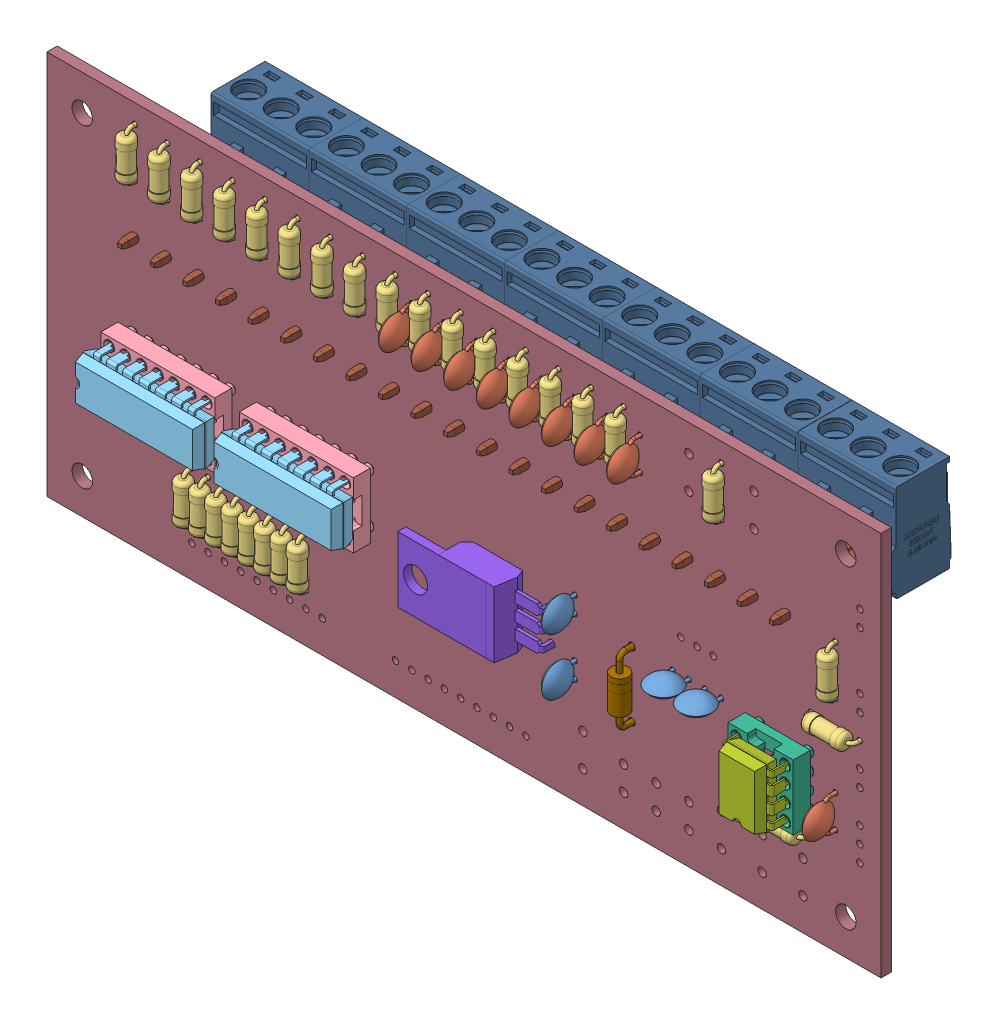
SolidWorks assembly minilab, configuration Predeterminado. Lengths in mm.
Overall size (130 60 30.78).
129 component instances, 13 part files, 0 mates.
Components (placement in the parent):
- C_Disc_D5.0mm_W2.5mm_P2.50mm-1: C_Disc_D5.0mm_W2.5mm_P2.50mm [Predeterminado] at (175.26 -113.03 1.65) x (0 -1 0) z (0 0 1) size (5 2.5 7.1)
  - SOLID_1-1: SOLID_1 [Predeterminado] at origin size (5 2.5 7.1)
- C_Disc_D5.0mm_W2.5mm_P5.00mm-1: C_Disc_D5.0mm_W2.5mm_P5.00mm [Predeterminado] at (170.18 -82.55 1.65) x (0 1 0) z (0 0 1) size (5.5 2.5 7.1)
  - SOLID_1_2-1: SOLID_1_2 [Predeterminado] at origin size (5.5 2.5 7.1)
- R_Axial_DIN0207_L6.3mm_D2.5mm_P7.62mm_Horizontal-1: R_Axial_DIN0207_L6.3mm_D2.5mm_P7.62mm_Horizontal [Predeterminado] at (121.92 -82.55 1.65) x (0 1 0) z (0 0 1) size (8.22 2.5 5.5)
  - SOLID_1_3-1: SOLID_1_3 [Predeterminado] at origin size (8.22 2.5 5.5)
- C_Disc_D5.0mm_W2.5mm_P2.50mm-2: C_Disc_D5.0mm_W2.5mm_P2.50mm [Predeterminado] at (190.52 -106.68 1.65) size (5 2.5 7.1)
  - SOLID_1-1: SOLID_1 [Predeterminado] at origin size (5 2.5 7.1)
- R_Axial_DIN0207_L6.3mm_D2.5mm_P7.62mm_Horizontal-2: R_Axial_DIN0207_L6.3mm_D2.5mm_P7.62mm_Horizontal [Predeterminado] at (182.88 -74.93 1.65) x (0 -1 0) z (0 0 1) size (8.22 2.5 5.5)
  - SOLID_1_3-1: SOLID_1_3 [Predeterminado] at origin size (8.22 2.5 5.5)
- R_Axial_DIN0207_L6.3mm_D2.5mm_P7.62mm_Horizontal-3: R_Axial_DIN0207_L6.3mm_D2.5mm_P7.62mm_Horizontal [Predeterminado] at (198.12 -82.55 1.65) x (0 1 0) z (0 0 1) size (8.22 2.5 5.5)
  - SOLID_1_3-1: SOLID_1_3 [Predeterminado] at origin size (8.22 2.5 5.5)
- C_Disc_D5.0mm_W2.5mm_P5.00mm-2: C_Disc_D5.0mm_W2.5mm_P5.00mm [Predeterminado] at (175.26 -82.51 1.65) x (0 1 0) z (0 0 1) size (5.5 2.5 7.1)
  - SOLID_1_2-1: SOLID_1_2 [Predeterminado] at origin size (5.5 2.5 7.1)
- DIP-14_W7.62mm_Socket-1: DIP-14_W7.62mm_Socket [Predeterminado] at (106.675 -110.48 1.65) x (0 1 0) z (0 0 1) size (10.16 17.78 7.79)
  - SOLID_1_4-1: SOLID_1_4 [Predeterminado] at origin size (10.16 17.78 7.79)
- DIP-14_W7.62mm_1-1: DIP-14_W7.62mm_1 [Predeterminado] at (106.675 -110.48 5.65) x (0 1 0) z (0 0 1) size (7.87 19.05 6.98)
  - SOLID_1_5-1: SOLID_1_5 [Predeterminado] at origin size (7.87 19.05 6.98)
- DIP-8_W7.62mm_Socket-1: DIP-8_W7.62mm_Socket [Predeterminado] at (212.06 -114.3 1.65) x (-1 0 0) z (0 0 1) size (10.16 10.16 7.79)
  - SOLID_1_6-1: SOLID_1_6 [Predeterminado] at origin size (10.16 10.16 7.79)
- DIP-8_W7.62mm_1-1: DIP-8_W7.62mm_1 [Predeterminado] at (212.06 -114.3 5.65) x (-1 0 0) z (0 0 1) size (7.87 9.27 6.98)
  - SOLID_1_7-1: SOLID_1_7 [Predeterminado] at origin size (7.87 9.27 6.98)
- R_Axial_DIN0207_L6.3mm_D2.5mm_P7.62mm_Horizontal-4: R_Axial_DIN0207_L6.3mm_D2.5mm_P7.62mm_Horizontal [Predeterminado] at (127 -82.55 1.65) x (0 1 0) z (0 0 1) size (8.22 2.5 5.5)
  - SOLID_1_3-1: SOLID_1_3 [Predeterminado] at origin size (8.22 2.5 5.5)
- R_Axial_DIN0207_L6.3mm_D2.5mm_P7.62mm_Horizontal-5: R_Axial_DIN0207_L6.3mm_D2.5mm_P7.62mm_Horizontal [Predeterminado] at (125.73 -116.84 1.65) x (0 -1 0) z (0 0 1) size (8.22 2.5 5.5)
  - SOLID_1_3-1: SOLID_1_3 [Predeterminado] at origin size (8.22 2.5 5.5)
- C_Disc_D5.0mm_W2.5mm_P5.00mm-3: C_Disc_D5.0mm_W2.5mm_P5.00mm [Predeterminado] at (149.86 -82.55 1.65) x (0 1 0) z (0 0 1) size (5.5 2.5 7.1)
  - SOLID_1_2-1: SOLID_1_2 [Predeterminado] at origin size (5.5 2.5 7.1)
- TO-220-3_Horizontal_TabUp-1: TO-220-3_Horizontal_TabUp [Predeterminado] at (171.66 -107.46 1.65) x (0 -1 0) z (0 0 1) size (10.25 19.74 12.58)
  - SOLID_1_8-1: SOLID_1_8 [Predeterminado] at origin size (10.25 19.74 12.58)
- R_Axial_DIN0207_L6.3mm_D2.5mm_P7.62mm_Horizontal-6: R_Axial_DIN0207_L6.3mm_D2.5mm_P7.62mm_Horizontal [Predeterminado] at (133.35 -116.84 1.65) x (0 -1 0) z (0 0 1) size (8.22 2.5 5.5)
  - SOLID_1_3-1: SOLID_1_3 [Predeterminado] at origin size (8.22 2.5 5.5)
- R_Axial_DIN0207_L6.3mm_D2.5mm_P7.62mm_Horizontal-7: R_Axial_DIN0207_L6.3mm_D2.5mm_P7.62mm_Horizontal [Predeterminado] at (120.65 -116.84 1.65) x (0 -1 0) z (0 0 1) size (8.22 2.5 5.5)
  - SOLID_1_3-1: SOLID_1_3 [Predeterminado] at origin size (8.22 2.5 5.5)
- C_Disc_D5.0mm_W2.5mm_P5.00mm-4: C_Disc_D5.0mm_W2.5mm_P5.00mm [Predeterminado] at (180.34 -82.51 1.65) x (0 1 0) z (0 0 1) size (5.5 2.5 7.1)
  - SOLID_1_2-1: SOLID_1_2 [Predeterminado] at origin size (5.5 2.5 7.1)
- R_Axial_DIN0207_L6.3mm_D2.5mm_P7.62mm_Horizontal-8: R_Axial_DIN0207_L6.3mm_D2.5mm_P7.62mm_Horizontal [Predeterminado] at (115.57 -116.84 1.65) x (0 -1 0) z (0 0 1) size (8.22 2.5 5.5)
  - SOLID_1_3-1: SOLID_1_3 [Predeterminado] at origin size (8.22 2.5 5.5)
- R_Axial_DIN0207_L6.3mm_D2.5mm_P7.62mm_Horizontal-9: R_Axial_DIN0207_L6.3mm_D2.5mm_P7.62mm_Horizontal [Predeterminado] at (157.48 -74.93 1.65) x (0 -1 0) z (0 0 1) size (8.22 2.5 5.5)
  - SOLID_1_3-1: SOLID_1_3 [Predeterminado] at origin size (8.22 2.5 5.5)
- R_Axial_DIN0207_L6.3mm_D2.5mm_P7.62mm_Horizontal-10: R_Axial_DIN0207_L6.3mm_D2.5mm_P7.62mm_Horizontal [Predeterminado] at (142.24 -82.55 1.65) x (0 1 0) z (0 0 1) size (8.22 2.5 5.5)
  - SOLID_1_3-1: SOLID_1_3 [Predeterminado] at origin size (8.22 2.5 5.5)
- C_Disc_D5.0mm_W2.5mm_P5.00mm-5: C_Disc_D5.0mm_W2.5mm_P5.00mm [Predeterminado] at (215.88 -110.54 1.65) x (0 -1 0) z (0 0 1) size (5.5 2.5 7.1)
  - SOLID_1_2-1: SOLID_1_2 [Predeterminado] at origin size (5.5 2.5 7.1)
- R_Axial_DIN0207_L6.3mm_D2.5mm_P7.62mm_Horizontal-11: R_Axial_DIN0207_L6.3mm_D2.5mm_P7.62mm_Horizontal [Predeterminado] at (123.19 -116.84 1.65) x (0 -1 0) z (0 0 1) size (8.22 2.5 5.5)
  - SOLID_1_3-1: SOLID_1_3 [Predeterminado] at origin size (8.22 2.5 5.5)
- D_DO-41_SOD81_P10.16mm_Horizontal-1: D_DO-41_SOD81_P10.16mm_Horizontal [Predeterminado] at (184.15 -106.68 1.65) x (0 -1 0) z (0 0 1) size (10.96 2.72 5.71)
  - SOLID_1_9-1: SOLID_1_9 [Predeterminado] at origin size (10.96 2.72 5.71)
- R_Axial_DIN0207_L6.3mm_D2.5mm_P7.62mm_Horizontal-12: R_Axial_DIN0207_L6.3mm_D2.5mm_P7.62mm_Horizontal [Predeterminado] at (116.84 -82.55 1.65) x (0 1 0) z (0 0 1) size (8.22 2.5 5.5)
  - SOLID_1_3-1: SOLID_1_3 [Predeterminado] at origin size (8.22 2.5 5.5)
- R_Axial_DIN0207_L6.3mm_D2.5mm_P7.62mm_Horizontal-13: R_Axial_DIN0207_L6.3mm_D2.5mm_P7.62mm_Horizontal [Predeterminado] at (132.08 -82.55 1.65) x (0 1 0) z (0 0 1) size (8.22 2.5 5.5)
  - SOLID_1_3-1: SOLID_1_3 [Predeterminado] at origin size (8.22 2.5 5.5)
- R_Axial_DIN0207_L6.3mm_D2.5mm_P7.62mm_Horizontal-14: R_Axial_DIN0207_L6.3mm_D2.5mm_P7.62mm_Horizontal [Predeterminado] at (172.72 -74.93 1.65) x (0 -1 0) z (0 0 1) size (8.22 2.5 5.5)
  - SOLID_1_3-1: SOLID_1_3 [Predeterminado] at origin size (8.22 2.5 5.5)
- R_Axial_DIN0207_L6.3mm_D2.5mm_P7.62mm_Horizontal-15: R_Axial_DIN0207_L6.3mm_D2.5mm_P7.62mm_Horizontal [Predeterminado] at (177.8 -74.93 1.65) x (0 -1 0) z (0 0 1) size (8.22 2.5 5.5)
  - SOLID_1_3-1: SOLID_1_3 [Predeterminado] at origin size (8.22 2.5 5.5)
- R_Axial_DIN0207_L6.3mm_D2.5mm_P7.62mm_Horizontal-16: R_Axial_DIN0207_L6.3mm_D2.5mm_P7.62mm_Horizontal [Predeterminado] at (111.76 -82.55 1.65) x (0 1 0) z (0 0 1) size (8.22 2.5 5.5)
  - SOLID_1_3-1: SOLID_1_3 [Predeterminado] at origin size (8.22 2.5 5.5)
- R_Axial_DIN0207_L6.3mm_D2.5mm_P7.62mm_Horizontal-17: R_Axial_DIN0207_L6.3mm_D2.5mm_P7.62mm_Horizontal [Predeterminado] at (128.27 -116.84 1.65) x (0 -1 0) z (0 0 1) size (8.22 2.5 5.5)
  - SOLID_1_3-1: SOLID_1_3 [Predeterminado] at origin size (8.22 2.5 5.5)
- C_Disc_D5.0mm_W2.5mm_P5.00mm-6: C_Disc_D5.0mm_W2.5mm_P5.00mm [Predeterminado] at (185.42 -82.51 1.65) x (0 1 0) z (0 0 1) size (5.5 2.5 7.1)
  - SOLID_1_2-1: SOLID_1_2 [Predeterminado] at origin size (5.5 2.5 7.1)
- C_Disc_D5.0mm_W2.5mm_P2.50mm-3: C_Disc_D5.0mm_W2.5mm_P2.50mm [Predeterminado] at (175.26 -106.68 1.65) x (0 1 0) z (0 0 1) size (5 2.5 7.1)
  - SOLID_1-1: SOLID_1 [Predeterminado] at origin size (5 2.5 7.1)
- C_Disc_D5.0mm_W2.5mm_P2.50mm-4: C_Disc_D5.0mm_W2.5mm_P2.50mm [Predeterminado] at (198.08 -106.68 1.65) x (-1 0 0) z (0 0 1) size (5 2.5 7.1)
  - SOLID_1-1: SOLID_1 [Predeterminado] at origin size (5 2.5 7.1)
- R_Axial_DIN0207_L6.3mm_D2.5mm_P7.62mm_Horizontal-18: R_Axial_DIN0207_L6.3mm_D2.5mm_P7.62mm_Horizontal [Predeterminado] at (215.9 -90.17 1.65) x (0 -1 0) z (0 0 1) size (8.22 2.5 5.5)
  - SOLID_1_3-1: SOLID_1_3 [Predeterminado] at origin size (8.22 2.5 5.5)
- R_Axial_DIN0207_L6.3mm_D2.5mm_P7.62mm_Horizontal-19: R_Axial_DIN0207_L6.3mm_D2.5mm_P7.62mm_Horizontal [Predeterminado] at (219.69 -101.61 1.65) x (-1 0 0) z (0 0 1) size (8.22 2.5 5.5)
  - SOLID_1_3-1: SOLID_1_3 [Predeterminado] at origin size (8.22 2.5 5.5)
- C_Disc_D5.0mm_W2.5mm_P5.00mm-7: C_Disc_D5.0mm_W2.5mm_P5.00mm [Predeterminado] at (160.02 -82.55 1.65) x (0 1 0) z (0 0 1) size (5.5 2.5 7.1)
  - SOLID_1_2-1: SOLID_1_2 [Predeterminado] at origin size (5.5 2.5 7.1)
- C_Disc_D5.0mm_W2.5mm_P5.00mm-8: C_Disc_D5.0mm_W2.5mm_P5.00mm [Predeterminado] at (165.1 -82.55 1.65) x (0 1 0) z (0 0 1) size (5.5 2.5 7.1)
  - SOLID_1_2-1: SOLID_1_2 [Predeterminado] at origin size (5.5 2.5 7.1)
- R_Axial_DIN0207_L6.3mm_D2.5mm_P7.62mm_Horizontal-20: R_Axial_DIN0207_L6.3mm_D2.5mm_P7.62mm_Horizontal [Predeterminado] at (137.16 -82.55 1.65) x (0 1 0) z (0 0 1) size (8.22 2.5 5.5)
  - SOLID_1_3-1: SOLID_1_3 [Predeterminado] at origin size (8.22 2.5 5.5)
- R_Axial_DIN0207_L6.3mm_D2.5mm_P7.62mm_Horizontal-21: R_Axial_DIN0207_L6.3mm_D2.5mm_P7.62mm_Horizontal [Predeterminado] at (130.81 -116.84 1.65) x (0 -1 0) z (0 0 1) size (8.22 2.5 5.5)
  - SOLID_1_3-1: SOLID_1_3 [Predeterminado] at origin size (8.22 2.5 5.5)
- R_Axial_DIN0207_L6.3mm_D2.5mm_P7.62mm_Horizontal-22: R_Axial_DIN0207_L6.3mm_D2.5mm_P7.62mm_Horizontal [Predeterminado] at (204.45 -118.12 1.65) size (8.22 2.5 5.5)
  - SOLID_1_3-1: SOLID_1_3 [Predeterminado] at origin size (8.22 2.5 5.5)
- R_Axial_DIN0207_L6.3mm_D2.5mm_P7.62mm_Horizontal-23: R_Axial_DIN0207_L6.3mm_D2.5mm_P7.62mm_Horizontal [Predeterminado] at (118.11 -116.84 1.65) x (0 -1 0) z (0 0 1) size (8.22 2.5 5.5)
  - SOLID_1_3-1: SOLID_1_3 [Predeterminado] at origin size (8.22 2.5 5.5)
- R_Axial_DIN0207_L6.3mm_D2.5mm_P7.62mm_Horizontal-24: R_Axial_DIN0207_L6.3mm_D2.5mm_P7.62mm_Horizontal [Predeterminado] at (106.68 -82.55 1.65) x (0 1 0) z (0 0 1) size (8.22 2.5 5.5)
  - SOLID_1_3-1: SOLID_1_3 [Predeterminado] at origin size (8.22 2.5 5.5)
- R_Axial_DIN0207_L6.3mm_D2.5mm_P7.62mm_Horizontal-25: R_Axial_DIN0207_L6.3mm_D2.5mm_P7.62mm_Horizontal [Predeterminado] at (167.64 -74.93 1.65) x (0 -1 0) z (0 0 1) size (8.22 2.5 5.5)
  - SOLID_1_3-1: SOLID_1_3 [Predeterminado] at origin size (8.22 2.5 5.5)
- R_Axial_DIN0207_L6.3mm_D2.5mm_P7.62mm_Horizontal-26: R_Axial_DIN0207_L6.3mm_D2.5mm_P7.62mm_Horizontal [Predeterminado] at (162.56 -74.93 1.65) x (0 -1 0) z (0 0 1) size (8.22 2.5 5.5)
  - SOLID_1_3-1: SOLID_1_3 [Predeterminado] at origin size (8.22 2.5 5.5)
- R_Axial_DIN0207_L6.3mm_D2.5mm_P7.62mm_Horizontal-27: R_Axial_DIN0207_L6.3mm_D2.5mm_P7.62mm_Horizontal [Predeterminado] at (147.32 -74.93 1.65) x (0 -1 0) z (0 0 1) size (8.22 2.5 5.5)
  - SOLID_1_3-1: SOLID_1_3 [Predeterminado] at origin size (8.22 2.5 5.5)
- DIP-14_W7.62mm_Socket-2: DIP-14_W7.62mm_Socket [Predeterminado] at (128.265 -110.48 1.65) x (0 1 0) z (0 0 1) size (10.16 17.78 7.79)
  - SOLID_1_4-1: SOLID_1_4 [Predeterminado] at origin size (10.16 17.78 7.79)
- DIP-14_W7.62mm_1-2: DIP-14_W7.62mm_1 [Predeterminado] at (128.265 -110.48 5.65) x (0 1 0) z (0 0 1) size (7.87 19.05 6.98)
  - SOLID_1_5-1: SOLID_1_5 [Predeterminado] at origin size (7.87 19.05 6.98)
- R_Axial_DIN0207_L6.3mm_D2.5mm_P7.62mm_Horizontal-28: R_Axial_DIN0207_L6.3mm_D2.5mm_P7.62mm_Horizontal [Predeterminado] at (152.4 -74.93 1.65) x (0 -1 0) z (0 0 1) size (8.22 2.5 5.5)
  - SOLID_1_3-1: SOLID_1_3 [Predeterminado] at origin size (8.22 2.5 5.5)
- C_Disc_D5.0mm_W2.5mm_P5.00mm-9: C_Disc_D5.0mm_W2.5mm_P5.00mm [Predeterminado] at (154.94 -82.55 1.65) x (0 1 0) z (0 0 1) size (5.5 2.5 7.1)
  - SOLID_1_2-1: SOLID_1_2 [Predeterminado] at origin size (5.5 2.5 7.1)
- 2EDGK-5.08-03P-14-00AH_1-1: 2EDGK-5.08-03P-14-00AH_1 [Predeterminado] at (104.14 -94.21 -4.05) x (1 0 0) z (0 1 0) size (15.24 17.4 15.1)
  - SOLID_1_10-1: SOLID_1_10 [Predeterminado] at origin size (15.24 17.4 15.1)
- 2EDGV-5.08-03P-14-00AH_1-1: 2EDGV-5.08-03P-14-00AH_1 [Predeterminado] at (104.14 -93.91 -0.05) x (1 0 0) z (0 1 0) size (15.24 16.1 8.2)
  - SOLID_1_11-1: SOLID_1_11 [Predeterminado] at origin size (15.24 16.1 8.2)
- 2EDGK-5.08-03P-14-00AH_1-2: 2EDGK-5.08-03P-14-00AH_1 [Predeterminado] at (134.62 -94.21 -4.05) x (1 0 0) z (0 1 0) size (15.24 17.4 15.1)
  - SOLID_1_10-1: SOLID_1_10 [Predeterminado] at origin size (15.24 17.4 15.1)
- 2EDGV-5.08-03P-14-00AH_1-2: 2EDGV-5.08-03P-14-00AH_1 [Predeterminado] at (134.62 -93.91 -0.05) x (1 0 0) z (0 1 0) size (15.24 16.1 8.2)
  - SOLID_1_11-1: SOLID_1_11 [Predeterminado] at origin size (15.24 16.1 8.2)
- 2EDGK-5.08-03P-14-00AH_1-3: 2EDGK-5.08-03P-14-00AH_1 [Predeterminado] at (149.86 -94.21 -4.05) x (1 0 0) z (0 1 0) size (15.24 17.4 15.1)
  - SOLID_1_10-1: SOLID_1_10 [Predeterminado] at origin size (15.24 17.4 15.1)
- 2EDGV-5.08-03P-14-00AH_1-3: 2EDGV-5.08-03P-14-00AH_1 [Predeterminado] at (149.86 -93.91 -0.05) x (1 0 0) z (0 1 0) size (15.24 16.1 8.2)
  - SOLID_1_11-1: SOLID_1_11 [Predeterminado] at origin size (15.24 16.1 8.2)
- SOIC-8-1EP_3.9x4.9mm_P1.27mm_EP2.35x2.35mm-1: SOIC-8-1EP_3.9x4.9mm_P1.27mm_EP2.35x2.35mm [Predeterminado] at (194.31 -114.3 -0.05) x (-1 0 0) z (0 0 -1) size (6 4.9 1.75)
  - SOLID_1_12-1: SOLID_1_12 [Predeterminado] at origin size (6 4.9 1.75)
- 2EDGK-5.08-03P-14-00AH_1-4: 2EDGK-5.08-03P-14-00AH_1 [Predeterminado] at (165.1 -94.21 -4.05) x (1 0 0) z (0 1 0) size (15.24 17.4 15.1)
  - SOLID_1_10-1: SOLID_1_10 [Predeterminado] at origin size (15.24 17.4 15.1)
- 2EDGV-5.08-03P-14-00AH_1-4: 2EDGV-5.08-03P-14-00AH_1 [Predeterminado] at (165.1 -93.91 -0.05) x (1 0 0) z (0 1 0) size (15.24 16.1 8.2)
  - SOLID_1_11-1: SOLID_1_11 [Predeterminado] at origin size (15.24 16.1 8.2)
- 2EDGK-5.08-03P-14-00AH_1-5: 2EDGK-5.08-03P-14-00AH_1 [Predeterminado] at (180.34 -94.21 -4.05) x (1 0 0) z (0 1 0) size (15.24 17.4 15.1)
  - SOLID_1_10-1: SOLID_1_10 [Predeterminado] at origin size (15.24 17.4 15.1)
- 2EDGV-5.08-03P-14-00AH_1-5: 2EDGV-5.08-03P-14-00AH_1 [Predeterminado] at (180.34 -93.91 -0.05) x (1 0 0) z (0 1 0) size (15.24 16.1 8.2)
  - SOLID_1_11-1: SOLID_1_11 [Predeterminado] at origin size (15.24 16.1 8.2)
- 2EDGK-5.08-03P-14-00AH_1-6: 2EDGK-5.08-03P-14-00AH_1 [Predeterminado] at (119.38 -94.21 -4.05) x (1 0 0) z (0 1 0) size (15.24 17.4 15.1)
  - SOLID_1_10-1: SOLID_1_10 [Predeterminado] at origin size (15.24 17.4 15.1)
- 2EDGV-5.08-03P-14-00AH_1-6: 2EDGV-5.08-03P-14-00AH_1 [Predeterminado] at (119.38 -93.91 -0.05) x (1 0 0) z (0 1 0) size (15.24 16.1 8.2)
  - SOLID_1_11-1: SOLID_1_11 [Predeterminado] at origin size (15.24 16.1 8.2)
- 2EDGK-5.08-03P-14-00AH_1-7: 2EDGK-5.08-03P-14-00AH_1 [Predeterminado] at (195.615 -94.21 -4.05) x (1 0 0) z (0 1 0) size (15.24 17.4 15.1)
  - SOLID_1_10-1: SOLID_1_10 [Predeterminado] at origin size (15.24 17.4 15.1)
- 2EDGV-5.08-03P-14-00AH_1-7: 2EDGV-5.08-03P-14-00AH_1 [Predeterminado] at (195.575 -93.91 -0.05) x (1 0 0) z (0 1 0) size (15.24 16.1 8.2)
  - SOLID_1_11-1: SOLID_1_11 [Predeterminado] at origin size (15.24 16.1 8.2)
- minilab PCB_1-1: minilab PCB_1 [Predeterminado] at origin size (130 60 1.6)
